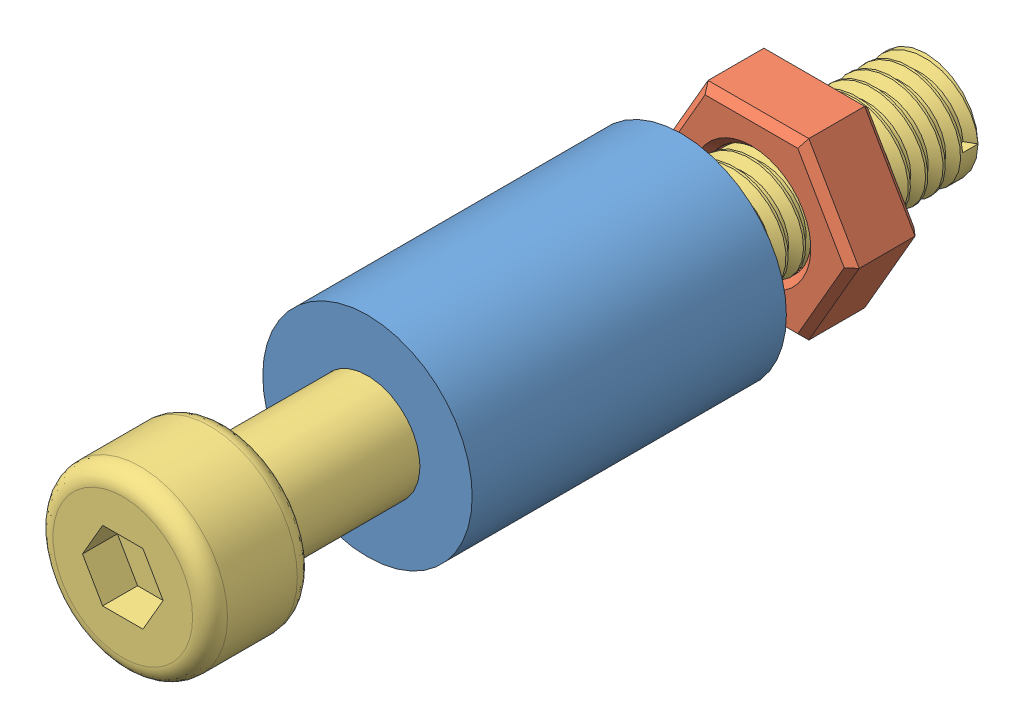
SolidWorks assembly Ajuste Display, configuration Predeterminado. Lengths in mm.
Overall size (6 6 23).
3 component instances, 3 part files, 4 mates.
Components (placement in the parent):
- Separador-1: Separador [Predeterminado] at (-0.7232 -0.23 17.4044) size (6 6 9)
- Tuerca M3-1: Tuerca M3 [Predeterminado] at (-0.7232 -0.23 13.4044) x (1 0 0) z (0 -1 0) size (5.77 2 5)
- Tornillo M3x20_CC-1: Tornillo M3x20_CC [Predeterminado] at (-0.7232 -0.23 10.4144) size (5 5 23)
Mates (geometry in assembly coordinates):
- Concéntrica2: concentric anti-aligned: cylinder of Separador-1 through (-0.7232 -0.23 26.4044) axis (0 0 -1) radius 3; circle of Tuerca M3-1
- Distancia2: distance = 2 mm anti-aligned: plane of Separador-1 through (-0.7232 -0.23 17.4044) normal (0 0 -1); plane of Tuerca M3-1 through (-0.7232 -0.23 15.4044) normal (0 0 1)
- Concéntrica3: concentric aligned: cylinder of Separador-1 through (-0.7232 -0.23 26.4044) axis (0 0 -1) radius 1.5; cylinder of Tornillo M3x20_CC-1 through (-0.7232 -0.23 30.4144) axis (0 0 -1) radius 1.5
- Distancia3: distance = 4.01 mm anti-aligned: plane of Tornillo M3x20_CC-1 through (-0.7232 -0.23 30.4144) normal (0 0 -1); plane of Separador-1 through (-0.7232 -0.23 26.4044) normal (0 0 1)
